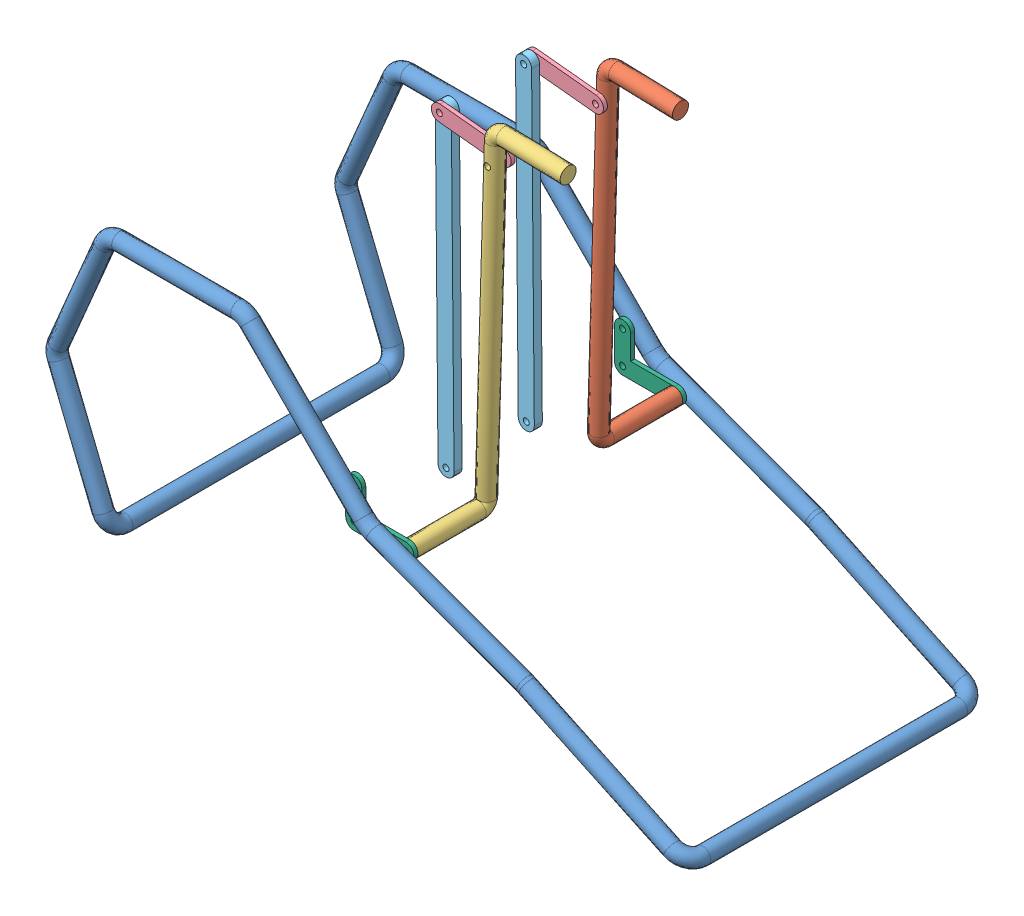
SolidWorks assembly Prototype, configuration Default. Lengths in mm.
Overall size (1021.84 740.84 482.6).
9 component instances, 6 part files, 21 mates.
Components (placement in the parent):
- Nubax Trio Frame-1: Nubax Trio Frame [Default] at (-437.8534 -203.7386 240.4024) size (1021.84 431.8 482.6)
- Support-2: Support [Default] at (19.3466 -9.1379 -197.7476) x (0.029814 0.999555 0) z (0 0 -1) size (546.1 127 133.35)
- Support 2-1: Support 2 [Default] at (19.3466 -9.1379 221.3524) x (0.029814 0.999555 0) z (0 0 1) size (546.1 127 133.35)
- Coupler-1: Coupler [Default] at (-16.9521 473.3466 81.6524) x (0.994794 -0.101904 0) z (0 0 1) size (127 25.4 6.35)
- Coupler-2: Coupler [Default] at (-16.9521 473.3466 -64.3976) x (0.994794 -0.101904 0) z (0 0 1) size (127 25.4 6.35)
- Rocker1-1: Rocker1 [Default] at (-65.3455 234.6927 -58.0476) x (0.999961 0.008785 0) z (0 0 1) size (25.4 513.08 12.7)
- Rocker1-2: Rocker1 [Default] at (-65.3455 234.6927 68.9524) x (0.999961 0.008785 0) z (0 0 1) size (25.4 513.08 12.7)
- Ground link support-1: Ground link support [Default] at (19.3466 -9.1379 221.3524) size (107.95 76.2 6.35)
- Ground link support-2: Ground link support [Default] at (19.3466 -9.1379 -204.0976) size (107.95 76.2 6.35)
Mates (geometry in assembly coordinates):
- Concentric2: concentric anti-aligned: cylinder of Nubax Trio Frame-1 through (19.3466 -9.1379 240.4024) axis (0 0 1) radius 4.7625; cylinder of Support-2 through (19.3466 -9.1379 -197.7476) axis (0 0 -1) radius 4.7625
- Concentric3: concentric aligned: cylinder of Nubax Trio Frame-1 through (19.3466 -9.1379 240.4024) axis (0 0 1) radius 4.7625; cylinder of Support 2-1 through (19.3466 -9.1379 221.3524) axis (0 0 1) radius 4.7625
- Coincident1: coincident aligned: plane of Support-2 through (149.12 507.9229 -77.0976) normal (0.999555 -0.029814 0); plane of Support 2-1 through (149.12 507.9229 100.7024) normal (0.999555 -0.029814 0)
- Concentric4: concentric anti-aligned: cylinder of Support 2-1 through (33.5834 468.1699 221.3524) axis (0 0 1) radius 4.7625; cylinder of Coupler-1 through (33.5834 468.1699 88.0024) axis (0 0 -1) radius 4.7625
- Concentric5: concentric aligned: cylinder of Support-2 through (33.5834 468.1699 -89.7976) axis (0 0 -1) radius 4.7625; cylinder of Coupler-2 through (33.5834 468.1699 -58.0476) axis (0 0 -1) radius 4.7625
- Concentric6: concentric aligned: cylinder of Coupler-1 through (-67.4877 478.5233 88.0024) axis (0 0 -1) radius 4.7625; cylinder of Rocker1-2 through (-67.4877 478.5233 81.6524) axis (0 0 -1) radius 4.7625
- Concentric7: concentric aligned: cylinder of Coupler-2 through (-67.4877 478.5233 -58.0476) axis (0 0 -1) radius 4.7625; cylinder of Rocker1-1 through (-67.4877 478.5233 -45.3476) axis (0 0 -1) radius 4.7625
- Tangent3: tangent anti-aligned: cylinder of Support 2-1 through (19.7252 3.5565 100.7024) axis (0.029814 0.999555 0) radius 12.7; plane of Coupler-1 through (-67.4877 478.5233 88.0024) normal (0 0 1)
- Tangent4: tangent anti-aligned: cylinder of Support-2 through (19.7252 3.5565 -77.0976) axis (0.029814 0.999555 0) radius 12.7; plane of Coupler-2 through (-67.4877 478.5233 -64.3976) normal (0 0 -1)
- Coincident2: coincident anti-aligned: plane of Coupler-2 through (-67.4877 478.5233 -58.0476) normal (0 0 1); plane of Rocker1-1 through (-67.4877 478.5233 -58.0476) normal (0 0 -1)
- Coincident3: coincident anti-aligned: plane of Coupler-1 through (-67.4877 478.5233 81.6524) normal (0 0 -1); plane of Rocker1-2 through (-67.4877 478.5233 81.6524) normal (0 0 1)
- Concentric8: concentric anti-aligned: circle of Support 2-1; cylinder of Ground link support-1 through (19.3466 -9.1379 227.7024) axis (0 0 -1) radius 4.7625
- Coincident6: coincident anti-aligned: plane of Support 2-1 through (19.3466 -9.1379 221.3524) normal (0 0 1); plane of Ground link support-1 through (19.3466 -9.1379 221.3524) normal (0 0 -1)
- Parallel1: parallel anti-aligned: plane of Ground link support-1 through (19.3466 -21.8379 227.7024) normal (0 -1 0); plane of assembly through (0 0 0) normal (0 1 0)
- Tangent5: tangent anti-aligned: cylinder of Nubax Trio Frame-1 through (220.3564 -83.223 240.4024) axis (-0.938299 0.345824 0) radius 12.7; plane of Ground link support-1 through (19.3466 -9.1379 227.7024) normal (0 0 1)
- Concentric9: concentric aligned: cylinder of Rocker1-2 through (-63.2034 -9.1379 81.6524) axis (0 0 -1) radius 4.7625; cylinder of Ground link support-1 through (-63.2034 -9.1379 227.7024) axis (0 0 -1) radius 4.7625
- Concentric10: concentric anti-aligned: cylinder of Nubax Trio Frame-1 through (19.3466 -9.1379 240.4024) axis (0 0 1) radius 4.7625; cylinder of Ground link support-2 through (19.3466 -9.1379 -197.7476) axis (0 0 -1) radius 4.7625
- Tangent6: tangent anti-aligned: cylinder of Nubax Trio Frame-1 through (-17.3086 4.3719 -216.7976) axis (0.938299 -0.345824 0) radius 12.7; plane of Ground link support-2 through (19.3466 -9.1379 -204.0976) normal (0 0 -1)
- Coincident7: coincident anti-aligned: plane of Support-2 through (19.3466 -9.1379 -197.7476) normal (0 0 -1); plane of Ground link support-2 through (19.3466 -9.1379 -197.7476) normal (0 0 1)
- Concentric11: concentric aligned: cylinder of Rocker1-1 through (-63.2034 -9.1379 -45.3476) axis (0 0 -1) radius 4.7625; cylinder of Ground link support-2 through (-63.2034 -9.1379 -197.7476) axis (0 0 -1) radius 4.7625
- Coincident9: coincident aligned: plane of Rocker1-1 through (-80.1872 478.4118 -45.3476) normal (-0.999961 -0.008785 0); plane of Rocker1-2 through (-80.1872 478.4118 81.6524) normal (-0.999961 -0.008785 0)
